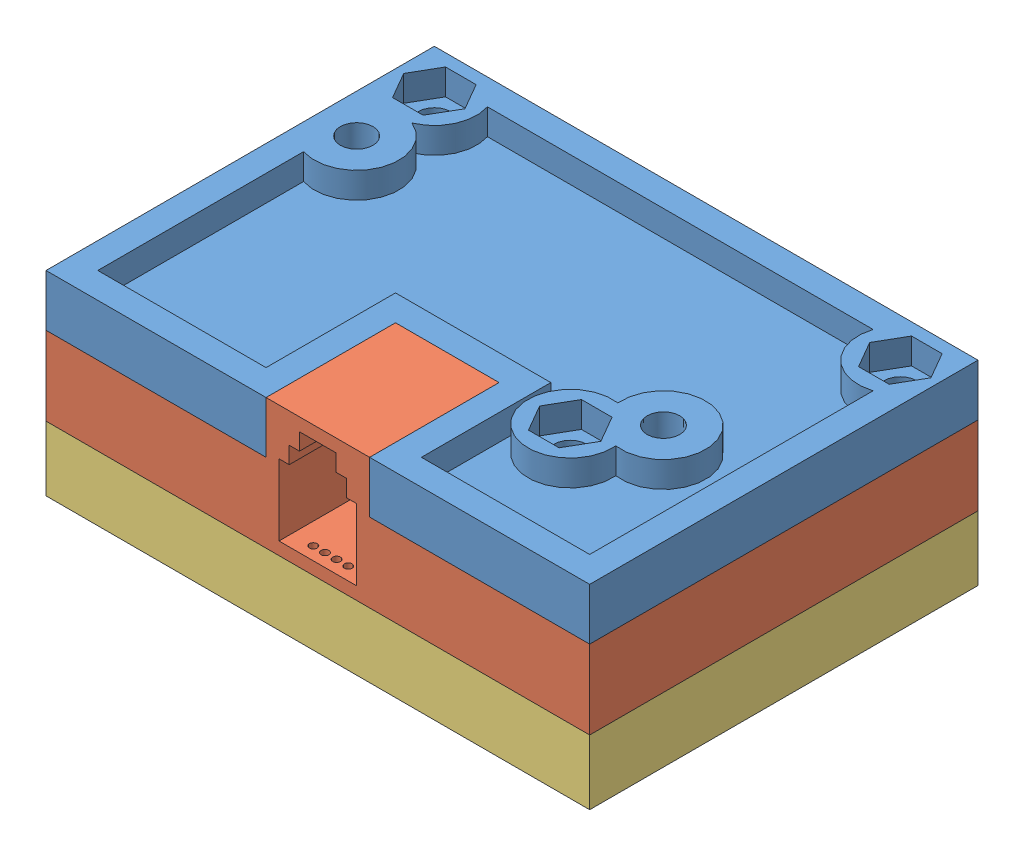
SolidWorks assembly boulderino, configuration Default. Lengths in mm.
Overall size (53.34 19.15 49.81).
3 component instances, 3 part files, 6 mates.
Components (placement in the parent):
- base-1: base [Default] at (-32.5873 -12.2299 25.5047) size (53.34 5.08 38.1)
- breadboard-1: breadboard [Default] at (-32.5873 -12.2299 25.5047) x (-1 0 0) z (0 0 1) size (53.34 13.31 49.81)
- top-1: top [Default] at (-32.5873 -19.9515 25.5047) x (1 0 0) z (0 0 -1) size (53.34 6.35 38.1)
Mates (geometry in assembly coordinates):
- Coincident13: coincident aligned: axis of breadboard-1 through (-9.7273 -19.9515 10.2647) axis (0 1 0); axis of top-1 through (-9.7273 -26.3015 10.2647) axis (0 1 0)
- Coincident15: coincident aligned: axis of breadboard-1 through (-55.4473 -19.9515 10.2647) axis (0 1 0); axis of top-1 through (-55.4473 -26.3015 10.2647) axis (0 1 0)
- Coincident17: coincident anti-aligned: axis of base-1 through (-9.7273 -9.6899 10.2647) axis (0 -1 0); axis of top-1 through (-9.7273 -26.3015 10.2647) axis (0 1 0)
- Coincident18: coincident anti-aligned: axis of base-1 through (-55.4473 -9.6899 10.2647) axis (0 -1 0); axis of breadboard-1 through (-55.4473 -19.9515 10.2647) axis (0 1 0)
- Coincident19: coincident: plane of breadboard-1 through (-5.9173 -19.9515 44.5547) normal (0 -1 0); line of top-1 through (-59.2573 -19.9515 6.4547) axis (1 0 0)
- Coincident20: coincident: plane of base-1 through (-37.6673 -12.2299 31.8547) normal (0 -1 0); line of breadboard-1 through (-59.2573 -12.2299 6.4547) axis (1 0 0)
